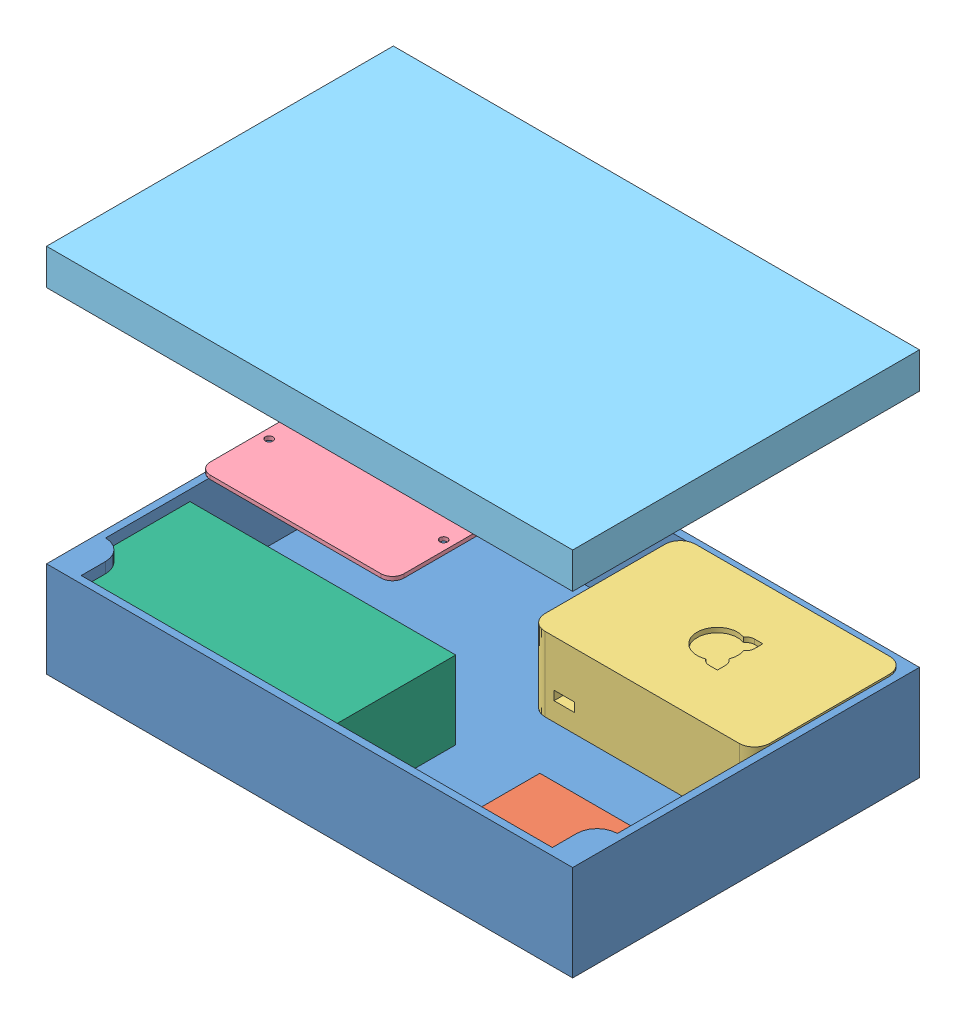
SolidWorks assembly PICase_Assembly_v3, configuration Default. Lengths in mm.
Overall size (220 155 145).
6 component instances, 6 part files, 16 mates.
Components (placement in the parent):
- PICase220x145x55_v1-1: PICase220x145x55_v1 [Default] at (-152.1826 -9.2207 87.4359) size (220 40 145)
- 12Vto5VMicroUsb_v1-1: 12Vto5VMicroUsb_v1 [Default] at (27.1126 -5.9238 53.4522) size (63 14 42)
- RaspberryPi3B_v1-1: RaspberryPi3B_v1 [Default] at (-29.1826 0.5457 8.4359) size (94 31 65.5)
- ProtoBoard_v1-1: ProtoBoard_v1 [Default] at (-143.4554 40.562 32.4786) size (80.96 1.59 50.8)
- PICase_LID_220x145x55_v1-1: PICase_LID_220x145x55_v1 [Default] at (-152.1826 145.7793 -57.5641) x (1 0 0) z (0 0 -1) size (220 15 145)
- PowerSupply_v2-1: PowerSupply_v2 [Default] at (-149.1826 -6.2207 84.4359) size (138.11 32.54 53.98)
Mates (geometry in assembly coordinates):
- Parallel1: parallel anti-aligned: plane of PICase220x145x55_v1-1 through (-152.1826 -6.2207 87.4359) normal (0 1 0); plane of RaspberryPi3B_v1-1 through (-29.1826 0.5457 8.4359) normal (0 -1 0)
- Parallel2: parallel anti-aligned: plane of PICase220x145x55_v1-1 through (-152.1826 -6.2207 87.4359) normal (0 1 0); plane of ProtoBoard_v1-1 through (-143.4554 40.562 32.4786) normal (0 -1 0)
- Parallel4: parallel anti-aligned: plane of PICase220x145x55_v1-1 through (-152.1826 -9.2207 87.4359) normal (0 -1 0); plane of PICase_LID_220x145x55_v1-1 through (-152.1826 145.7793 -57.5641) normal (0 1 0)
- Coincident6: coincident aligned: plane of PICase220x145x55_v1-1 through (-152.1826 -6.2207 87.4359) normal (-1 0 0); plane of PICase_LID_220x145x55_v1-1 through (-152.1826 142.7793 -57.5641) normal (-1 0 0)
- Coincident9: coincident aligned: plane of PICase220x145x55_v1-1 through (-152.1826 -6.2207 87.4359) normal (0 0 1); plane of PICase_LID_220x145x55_v1-1 through (-152.1826 142.7793 87.4359) normal (0 0 1)
- LimitDistance1: limit distance = 100 mm anti-aligned: plane of PICase220x145x55_v1-1 through (-152.1826 30.7793 87.4359) normal (0 1 0); plane of PICase_LID_220x145x55_v1-1 through (-152.1826 130.7793 -57.5641) normal (0 -1 0)
- LimitDistance2: limit distance = 6.7664 mm anti-aligned: plane of RaspberryPi3B_v1-1 through (-29.1826 0.5457 8.4359) normal (0 -1 0); plane of PICase220x145x55_v1-1 through (-152.1826 -6.2207 87.4359) normal (0 1 0)
- LimitDistance4: limit distance = 120 mm anti-aligned: plane of RaspberryPi3B_v1-1 through (-29.1826 31.5457 8.4359) normal (-1 0 0); plane of PICase220x145x55_v1-1 through (-149.1826 334.2655 -35.8641) normal (1 0 0)
- LimitDistance6: limit distance = 76 mm anti-aligned: plane of PICase220x145x55_v1-1 through (-140.6826 334.2655 84.4359) normal (0 0 -1); plane of RaspberryPi3B_v1-1 through (-29.1826 31.5457 8.4359) normal (0 0 1)
- LimitDistance5: limit distance = 6.7664 mm anti-aligned: plane of RaspberryPi3B_v1-1 through (-29.1826 0.5457 8.4359) normal (0 -1 0); plane of PICase220x145x55_v1-1 through (-152.1826 -6.2207 87.4359) normal (0 1 0)
- Parallel5: parallel anti-aligned: plane of PICase220x145x55_v1-1 through (-152.1826 -6.2207 87.4359) normal (0 1 0); plane of PowerSupply_v2-1 through (-149.1826 -6.2207 84.4359) normal (0 -1 0)
- Parallel6: parallel aligned: plane of PICase220x145x55_v1-1 through (-152.1826 -6.2207 87.4359) normal (0 0 1); plane of PowerSupply_v2-1 through (-149.1826 26.323 84.4359) normal (0 0 1)
- Parallel7: parallel aligned: plane of PICase220x145x55_v1-1 through (-152.1826 -6.2207 87.4359) normal (-1 0 0); plane of PowerSupply_v2-1 through (-149.1826 26.323 84.4359) normal (-1 0 0)
- LimitDistance7: limit distance = 0 mm anti-aligned: plane of PowerSupply_v2-1 through (-149.1826 26.323 84.4359) normal (-1 0 0); plane of PICase220x145x55_v1-1 through (-149.1826 334.2655 -35.8641) normal (1 0 0)
- LimitDistance8: limit distance = 0 mm anti-aligned: plane of PowerSupply_v2-1 through (-149.1826 26.323 84.4359) normal (0 0 1); plane of PICase220x145x55_v1-1 through (-140.6826 334.2655 84.4359) normal (0 0 -1)
- LimitDistance9: limit distance = 0 mm anti-aligned: plane of PowerSupply_v2-1 through (-149.1826 -6.2207 84.4359) normal (0 -1 0); plane of PICase220x145x55_v1-1 through (-152.1826 -6.2207 87.4359) normal (0 1 0)
